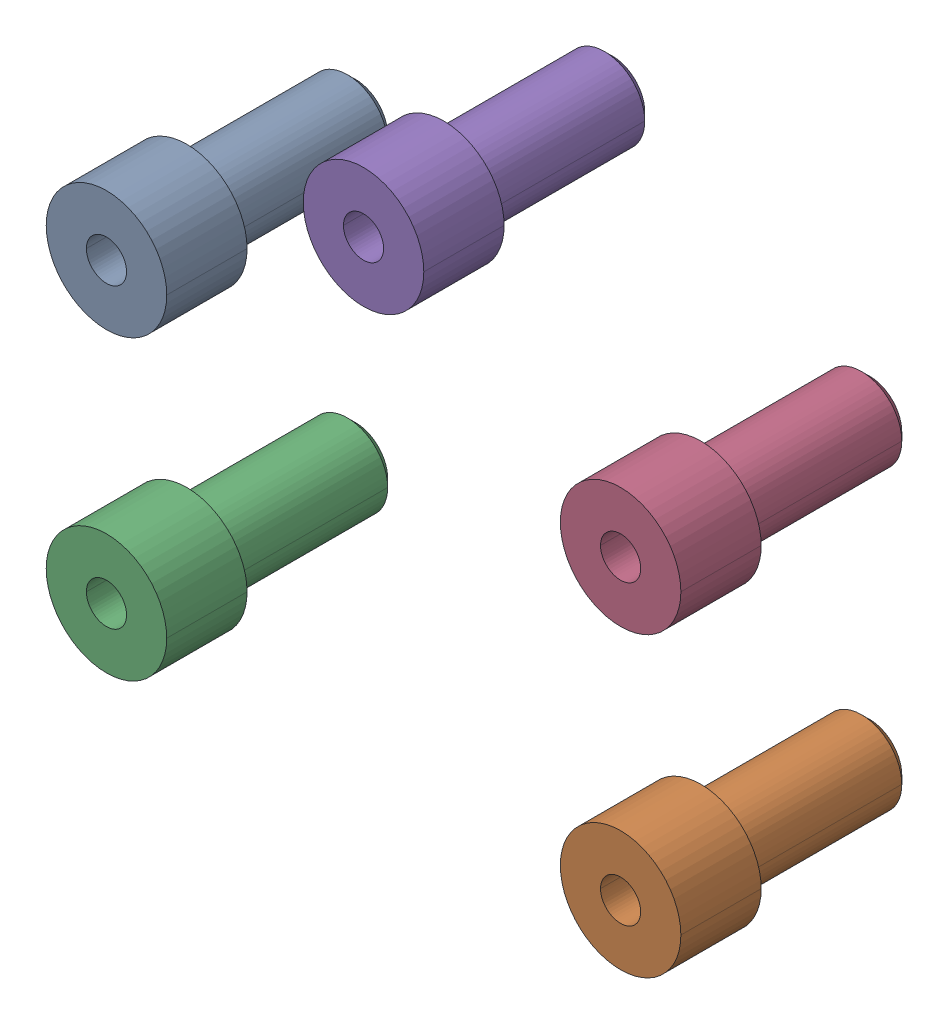
SolidWorks assembly JP2.step, configuration Default. Lengths in mm.
Overall size (15.8 14.1 6.2).
5 component instances, 1 part files, 0 mates.
Components (placement in the parent):
- __________.step-1: __________.step [Default] at (-6.3999 3.7001 0) size (3 3 6.2)
- __________.step-2: __________.step [Default] at (6.4001 -3.7 0) size (3 3 6.2)
- __________.step-3: __________.step [Default] at (-6.3999 -3.6999 0) size (3 3 6.2)
- __________.step-4: __________.step [Default] at (6.4001 3.7001 0) size (3 3 6.2)
- __________.step-5: __________.step [Default] at (0.0001 7.4001 0) size (3 3 6.2)
